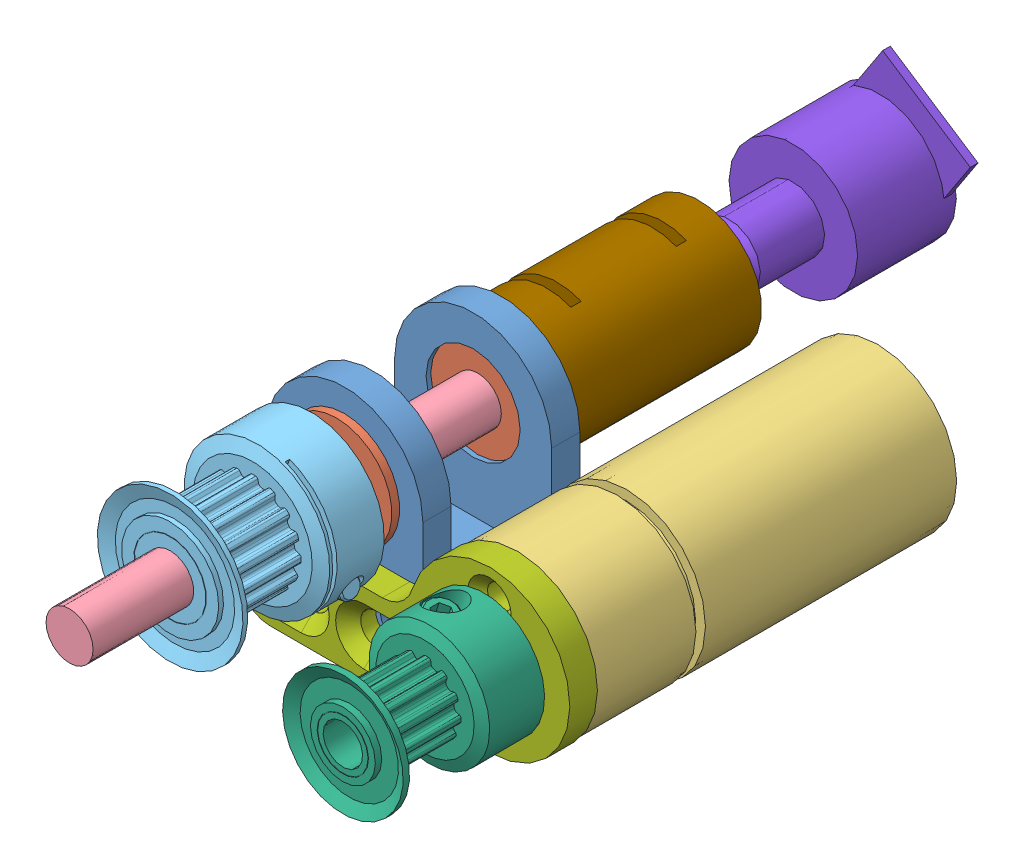
SolidWorks assembly head-pin-joint, configuration Default. Lengths in mm.
Overall size (48.11 26.33 83.16).
11 component instances, 10 part files, 22 mates.
Components (placement in the parent):
- n05-headyoke-1: n05-headyoke [Default] at origin size (15.88 21.91 15.88)
- p1875bearing-57155K319-MCM-1: p1875bearing-57155K319-MCM [Default] at (0 13.97 5.5499) x (0 0 -1) z (0 -1 0) size (3.17 11.18 11.18)
- p1875bearing-57155K319-MCM-2: p1875bearing-57155K319-MCM [Default] at (0 13.97 -5.5499) x (0 0 1) z (0 -1 0) size (3.17 11.18 11.18)
- MAXON-AMAX16-110049-110323-1: MAXON-AMAX16-110049-110323 [Default] at (17.4625 8.128 -28.5125) x (0 0 -1) z (1 0 0) size (48.2 16 16)
- n06-p1875shaft-1: n06-p1875shaft [Default] at (0 13.97 -15.0749) size (4.76 4.76 50.8)
- a_6d16-016df2506-p1875bore-16teeth-1: a_6d16-016df2506-p1875bore-16teeth [Default] at (0 13.97 17.218) x (0.167713 -0.985836 0) z (0 0 -1) size (14.73 14.73 14.29)
- a_6d16m012df6003-3mm-bored-to-4mm-1: a_6d16m012df6003-3mm-bored-to-4mm [Default] at (17.4625 8.128 17.2524) x (-0.948708 0.316155 0) z (0 0 -1) size (12.2 12.2 14.3)
- a_6n16-015df1206-2: a_6n16-015df1206 [Default] at (-14.2838 6.954 15.9813) x (0.986257 0.164531 -0.015045) z (-0.021924 0.040076 -0.998956) size (14.1 14.1 11.13) (hidden)
- n09-motor-holder-1: n09-motor-holder [Default] at (17.4625 8.128 7.9375) size (33.53 16.26 2.79)
- POT-eti-sys-EUP125-1: POT-eti-sys-EUP125 [Default] at (0 13.97 -47.4345) x (0 0 -1) z (0.836462 -0.548026 0) size (30.58 15.39 13)
- 000_helical-coupling-6208K53-MCM-1: 000_helical-coupling-6208K53-MCM [Default] at (0 13.97 -18.3769) size (12.7 12.7 19.05)
Mates (geometry in assembly coordinates):
- Coincident1: coincident anti-aligned: plane of n05-headyoke-1 through (0 13.97 7.9375) normal (0 0 1); plane of p1875bearing-57155K319-MCM-1 through (4.7625 13.97 7.9375) normal (0 0 -1)
- Coincident2: coincident anti-aligned: plane of n05-headyoke-1 through (0 13.97 -7.9375) normal (0 0 -1); plane of p1875bearing-57155K319-MCM-2 through (-4.7625 13.97 -7.9375) normal (0 0 1)
- Concentric1: concentric anti-aligned: cylinder of n05-headyoke-1; cylinder of p1875bearing-57155K319-MCM-2
- Concentric2: concentric aligned: cylinder of n05-headyoke-1; cylinder of p1875bearing-57155K319-MCM-1
- Coincident3: coincident anti-aligned: plane of p1875bearing-57155K319-MCM-1 through (0 13.97 5.5499) normal (1 0 0); plane of p1875bearing-57155K319-MCM-2 through (0 13.97 -5.5499) normal (-1 0 0)
- Parallel1: parallel aligned: plane of n05-headyoke-1 through (7.9375 0 7.9375) normal (1 0 0); plane of p1875bearing-57155K319-MCM-1 through (0 13.97 5.5499) normal (1 0 0)
- Concentric3: concentric anti-aligned: cylinder of p1875bearing-57155K319-MCM-2; cylinder of n06-p1875shaft-1
- Distance1: distance = 6.35 mm aligned: plane of p1875bearing-57155K319-MCM-2 through (-5.588 13.97 -8.7249) normal (0 0 -1); plane of n06-p1875shaft-1 through (0 13.97 -15.0749) normal (0 0 -1)
- Concentric4: concentric aligned: cylinder of n06-p1875shaft-1; cylinder of a_6d16-016df2506-p1875bore-16teeth-1
- Distance2: distance = 2.54 mm anti-aligned: plane of p1875bearing-57155K319-MCM-1 through (5.588 13.97 8.7249) normal (0 0 1); plane of a_6d16-016df2506-p1875bore-16teeth-1 through (-7.2617 12.7346 11.2649) normal (0 0 -1)
- Coincident7: coincident aligned: plane of n05-headyoke-1 through (0 13.97 7.9375) normal (0 0 1); plane of MAXON-AMAX16-110049-110323-1 through (17.4625 16.128 7.9375) normal (0 0 1)
- Concentric5: concentric aligned: cylinder of MAXON-AMAX16-110049-110323-1; cylinder of a_6d16m012df6003-3mm-bored-to-4mm-1
- Coincident8: coincident aligned: plane of a_6d16-016df2506-p1875bore-16teeth-1 through (0 13.97 25.5524) normal (0 0 1); plane of a_6d16m012df6003-3mm-bored-to-4mm-1 through (17.4625 8.128 25.5524) normal (0 0 1)
- Concentric6: concentric aligned: cylinder of MAXON-AMAX16-110049-110323-1; cylinder of n09-motor-holder-1
- Coincident9: coincident anti-aligned: plane of MAXON-AMAX16-110049-110323-1; plane of n09-motor-holder-1 through (17.4625 8.128 7.9375) normal (0 0 -1)
- Concentric7: concentric anti-aligned: cylinder of n05-headyoke-1; cylinder of n09-motor-holder-1
- Concentric8: concentric anti-aligned: cylinder of n05-headyoke-1; cylinder of n09-motor-holder-1
- Concentric9: concentric aligned: cylinder of MAXON-AMAX16-110049-110323-1; cylinder of n09-motor-holder-1
- Distance3: distance = 0.127 mm anti-aligned: plane of p1875bearing-57155K319-MCM-2; plane of 000_helical-coupling-6208K53-MCM-1 through (0 13.97 -8.8519) normal (0 0 1)
- Concentric10: concentric aligned: cylinder of n06-p1875shaft-1; cylinder of 000_helical-coupling-6208K53-MCM-1
- Distance4: distance = 2.54 mm anti-aligned: plane of POT-eti-sys-EUP125-1 through (1.74 16.6258 -30.4419) normal (0 0 1); plane of 000_helical-coupling-6208K53-MCM-1 through (0 13.97 -27.9019) normal (0 0 -1)
- Concentric11: concentric aligned: cylinder of POT-eti-sys-EUP125-1; cylinder of 000_helical-coupling-6208K53-MCM-1
